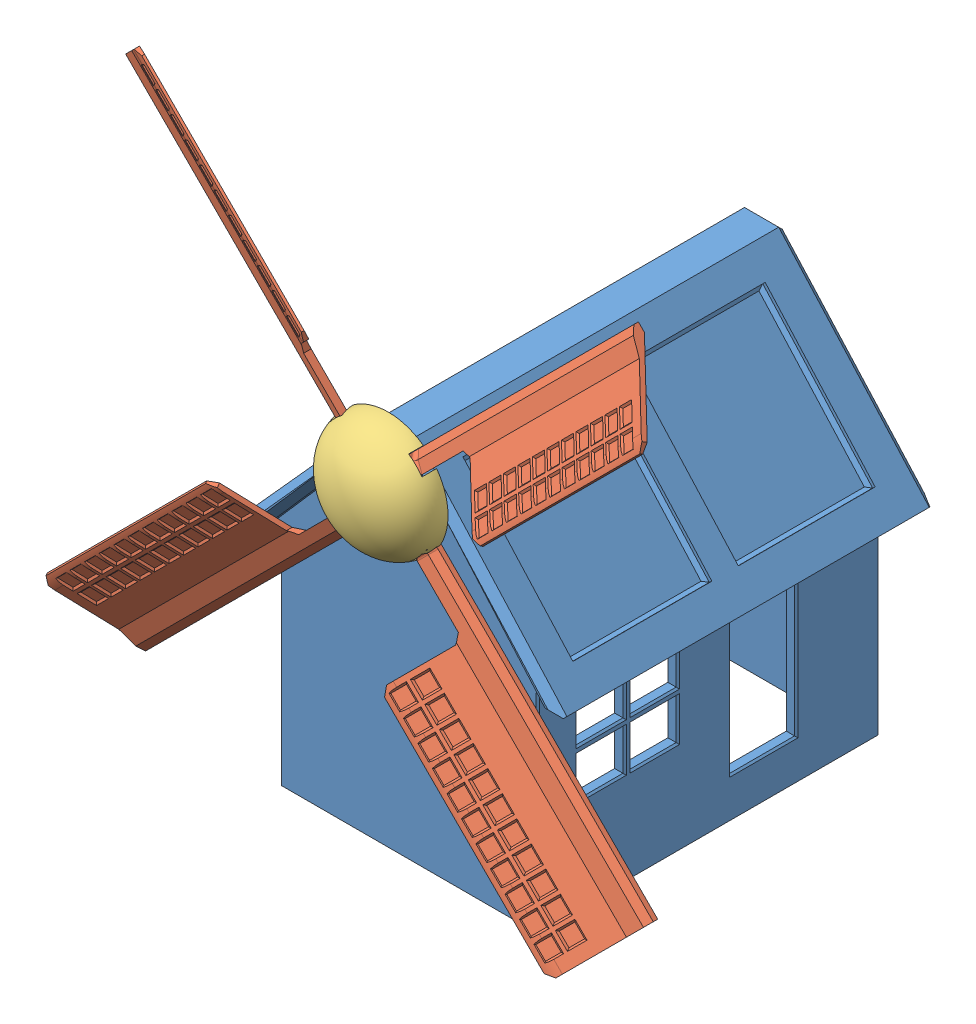
SolidWorks assembly windmill, configuration Default. Lengths in mm.
Overall size (177.01 186.03 124.92).
6 component instances, 3 part files, 0 mates.
Components (placement in the parent):
- house-1: house [Default] at (-3.0986 105.7828 108.7347) size (97.71 111.18 110)
- blade-1: blade [Default] at (7.259 80.8094 163.6512) x (0.707107 0.707107 0) z (0.707107 -0.707107 0) size (24.17 15 105)
- blade-2: blade [Default] at (8.6732 102.0226 163.6512) x (-0.707107 0.707107 0) z (0.707107 0.707107 0) size (24.17 15 105)
- blade-3: blade [Default] at (-12.54 103.4368 163.6512) x (-0.707107 -0.707107 0) z (-0.707107 0.707107 0) size (24.17 15 105)
- blade-4: blade [Default] at (-13.9542 82.2236 163.6512) x (0.707107 -0.707107 0) z (-0.707107 -0.707107 0) size (24.17 15 105)
- centerlock-1: centerlock [Default] at (-4.012 92.6539 162.4007) x (0.707107 0.707107 0) z (0.707107 -0.707107 0) size (36.06 13.12 36.06)
